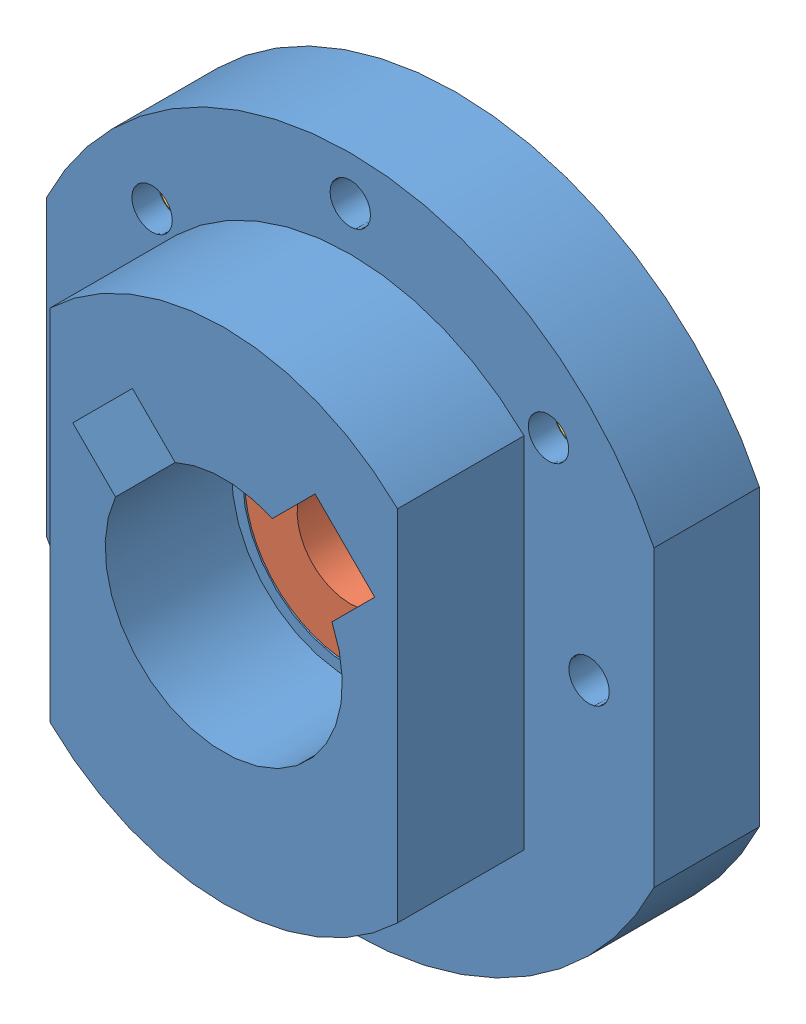
SolidWorks assembly Wing Fold Mechanism Lower Cap, configuration Default. Lengths in mm.
Overall size (36.58 40.64 13.97).
4 component instances, 3 part files, 0 mates.
Components (placement in the parent):
- Wing Fold Mechanism Lower Cap-1: Wing Fold Mechanism Lower Cap [Default] at origin size (36.58 40.64 13.97)
- 6338K411 (1)-1: 6338K411 (1) [Default] at (0 0 -7.9375) x (1 0 0) z (0 1 0) size (12.7 6.35 12.7)
- 93365A112-1: 93365A112 [Default] at (11.938 11.43 -14.2875) x (1 0 0) z (0 1 0) size (3.58 4.78 3.58)
- 93365A112-2: 93365A112 [Default] at (-11.938 11.43 -14.2875) x (1 0 0) z (0 1 0) size (3.58 4.78 3.58)
